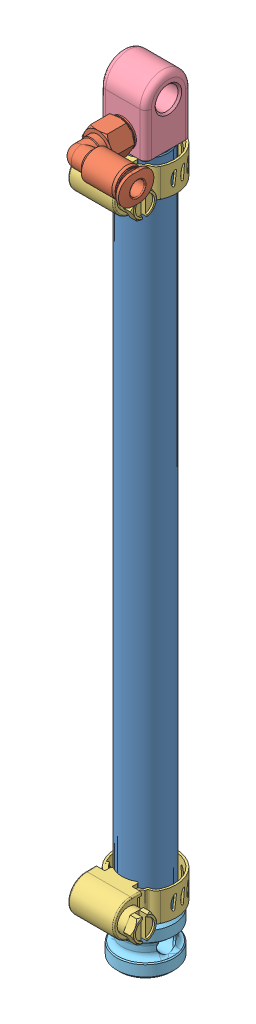
SolidWorks assembly AARL_QR_PN_PA_BL_KN_FL-Flexor, configuration Default. Lengths in mm.
Overall size (24.22 215.9 31.28).
6 component instances, 5 part files, 15 mates.
Components (placement in the parent):
- AARL_QR_PN_PA_BL_KN_FL_001-1: AARL_QR_PN_PA_BL_KN_FL_001 [Resting] at origin size (12.7 184.15 12.7)
- AARL_Puppy_18_02_57_010-QSML-M3-4-1: AARL_Puppy_18_02_57_010-QSML-M3-4 [Default] at (0 96.8375 17.85) x (1 0 0) z (0 0 -1) size (20.32 8 18.9)
- AARL_Puppy_18_02_57_011-5388K140_Hose-Clamp-1: AARL_Puppy_18_02_57_011-5388K140_Hose-Clamp [5388K14] at (0 87.122 0) x (1 0 0) z (0 -1 0) size (19.43 23.71 9.91)
- AARL_Puppy_18_02_57_011-5388K140_Hose-Clamp-2: AARL_Puppy_18_02_57_011-5388K140_Hose-Clamp [5388K14] at (0 -87.122 0) x (1 0 0) z (0 -1 0) size (19.43 23.71 9.91)
- AARL_QR_PN_EP_001-1: AARL_QR_PN_EP_001 [Default] at (0 104.775 0) x (0 0 1) z (-1 0 0) size (12.7 31.75 12.7)
- AARL_QR_PN_EP_002-1: AARL_QR_PN_EP_002 [Default] at (0 -92.075 0) x (-1 0 0) z (0 0 1) size (15.88 25.4 15.88)
Mates (geometry in assembly coordinates):
- Concentric1: concentric aligned: cylinder of AARL_QR_PN_PA_BL_KN_FL_001-1 through (0 11.6086 0) axis (0 1 0) radius 4.7625; cylinder of AARL_QR_PN_EP_001-1 through (0 114.319 0) axis (0 1 0) radius 4.3656
- Parallel1: parallel aligned: plane of AARL_QR_PN_EP_001-1 through (-6.35 92.075 6.35) normal (0 0 1)
- Coincident2: coincident anti-aligned: plane of AARL_QR_PN_PA_BL_KN_FL_001-1 through (4.7625 92.075 0) normal (0 1 0); plane of AARL_QR_PN_EP_001-1 through (-6.35 92.075 -6.35) normal (0 -1 0)
- Concentric2: concentric aligned: cylinder of AARL_Puppy_18_02_57_010-QSML-M3-4-1 through (0 96.8375 6.35) axis (0 0 1) radius 1.5; cylinder of AARL_QR_PN_EP_001-1 through (0 96.8375 6.35) axis (0 0 1) radius 2.0193
- Parallel2: parallel anti-aligned: plane of AARL_Puppy_18_02_57_010-QSML-M3-4-1 through (-2.3094 100.8375 13.4056) normal (0 1 0); plane of AARL_QR_PN_EP_001-1 through (-6.35 92.075 -6.35) normal (0 -1 0)
- Coincident4: coincident anti-aligned: plane of AARL_Puppy_18_02_57_010-QSML-M3-4-1 through (0 96.8375 6.35) normal (0 0 -1); plane of AARL_QR_PN_EP_001-1 through (-6.35 92.075 6.35) normal (0 0 1)
- Concentric3: concentric anti-aligned: cylinder of AARL_QR_PN_PA_BL_KN_FL_001-1 through (0 11.6086 0) axis (0 1 0) radius 4.7625; cylinder of AARL_QR_PN_EP_002-1 through (0 -99.8127 0) axis (0 -1 0) radius 4.3656
- Coincident5: coincident anti-aligned: plane of AARL_QR_PN_PA_BL_KN_FL_001-1 through (6.35 -92.075 0) normal (0 -1 0); plane of AARL_QR_PN_EP_002-1 through (-4.3656 -92.075 0) normal (0 1 0)
- Parallel3: parallel anti-aligned: cylinder of AARL_QR_PN_EP_001-1 through (-6.35 104.775 0) axis (1 0 0) radius 3.175; cylinder of AARL_QR_PN_EP_002-1 through (7.9375 -98.425 0) axis (-1 0 0) radius 2.3813
- Concentric5: concentric aligned: cylinder of AARL_QR_PN_PA_BL_KN_FL_001-1 through (0 11.6086 0) axis (0 1 0) radius 6.35; cylinder of AARL_Puppy_18_02_57_011-5388K140_Hose-Clamp-1 through (0 83.1532 0) axis (0 1 0) radius 7.9375
- Coincident6: coincident aligned: plane of AARL_Puppy_18_02_57_011-5388K140_Hose-Clamp-1 through (6.35 87.122 10.2337) normal (1 0 0); plane of AARL_QR_PN_EP_001-1 through (6.35 104.775 0) normal (1 0 0)
- Coincident7: coincident anti-aligned: plane of AARL_Puppy_18_02_57_011-5388K140_Hose-Clamp-1 through (0 92.075 0) normal (0 1 0); plane of AARL_QR_PN_EP_001-1 through (-6.35 92.075 -6.35) normal (0 -1 0)
- Concentric6: concentric aligned: cylinder of AARL_QR_PN_PA_BL_KN_FL_001-1 through (0 11.6086 0) axis (0 1 0) radius 6.35; cylinder of AARL_Puppy_18_02_57_011-5388K140_Hose-Clamp-2 through (0 -91.0907 0) axis (0 1 0) radius 7.9375
- Coincident8: coincident aligned: plane of AARL_Puppy_18_02_57_011-5388K140_Hose-Clamp-1 through (6.35 87.122 10.2337) normal (1 0 0); plane of AARL_Puppy_18_02_57_011-5388K140_Hose-Clamp-2 through (6.35 -87.122 10.2337) normal (1 0 0)
- Coincident9: coincident: plane of AARL_Puppy_18_02_57_011-5388K140_Hose-Clamp-2 through (0 -92.075 0) normal (0 -1 0); plane of AARL_QR_PN_EP_002-1 through (-4.3656 -92.075 0) normal (0 1 0)
